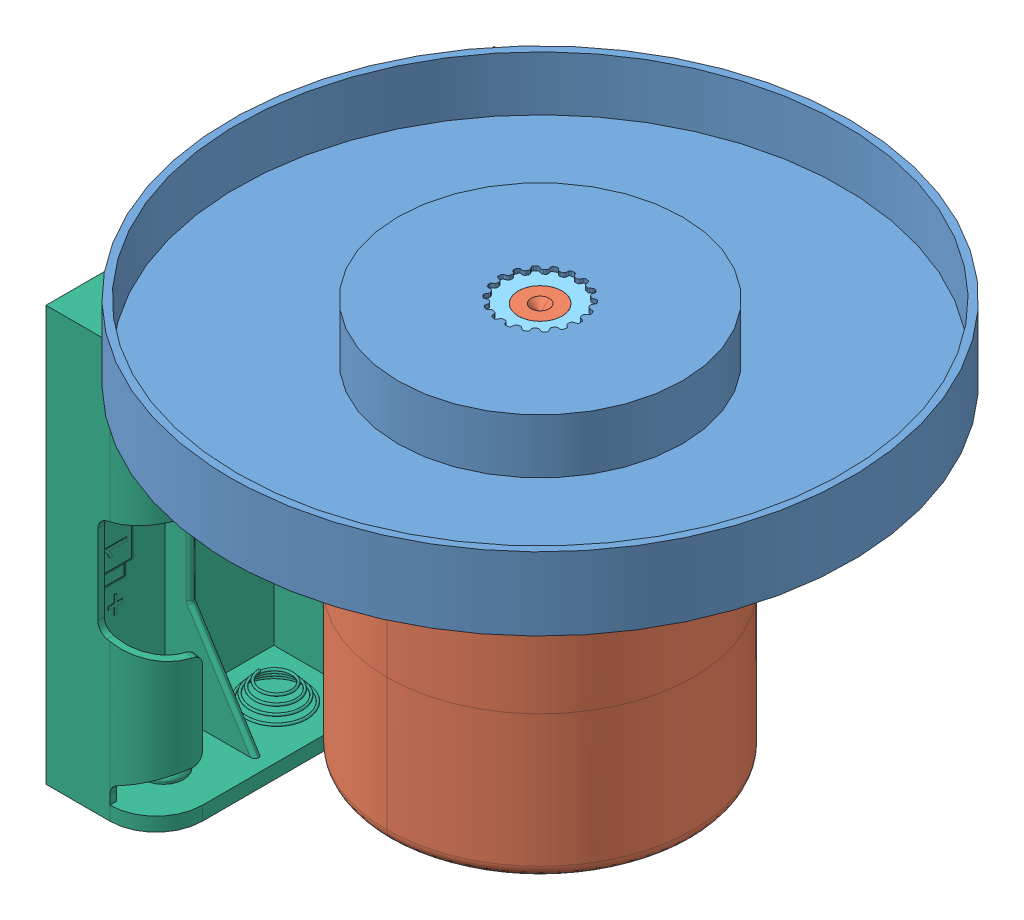
SolidWorks assembly Assem, configuration Default. Lengths in mm.
Overall size (93.99 75.26 87.69).
9 component instances, 6 part files, 2 mates.
Components (placement in the parent):
- Wheel-1: Wheel [Default] at (109.0913 123.8958 121.3791) size (85 10 85)
- Assem1.STEP-1: Assem1.STEP [Default] at (109.0913 99.4458 121.3791) size (69.62 53.75 56.99)
  - motor.STEP-1: motor.STEP [Default] at origin size (48.19 53.75 42)
  - mount_plate.STEP-1: mount_plate.STEP [Default] at (0 14.3 0) x (0.961464 0 -0.274932) z (0.274932 0 0.961464) size (60.4 5.33 42)
  - pan head cross recess screw_iso_ISO 7045 - M3 x 4 - Z - 4N.STEP-1: pan head cross recess screw_iso_ISO 7045 - M3 x 4 - Z - 4N.STEP [Default] at (0 17.78 -15) x (0 -1 0) z (0 0 1) size (6.36 5.6 5.6)
  - pan head cross recess screw_iso_ISO 7045 - M3 x 4 - Z - 4N.STEP-2: pan head cross recess screw_iso_ISO 7045 - M3 x 4 - Z - 4N.STEP [Default] at (-12.9904 17.78 7.5) x (0 -1 0) z (0 0 1) size (6.36 5.6 5.6)
  - pan head cross recess screw_iso_ISO 7045 - M3 x 4 - Z - 4N.STEP-3: pan head cross recess screw_iso_ISO 7045 - M3 x 4 - Z - 4N.STEP [Default] at (12.9904 17.78 7.5) x (0 -1 0) z (0 0 1) size (6.36 5.6 5.6)
  - pulley_nidec.STEP-1: pulley_nidec.STEP [Default] at (0 33.9 0) x (1 0 0) z (0 1 0) size (15 15 11.6)
- Battery2-1: Battery2 [Default] at (57.6046 87.0879 106.9276) x (0 1 0) z (1 0 0) size (59.56 61.47 15.11)
Mates (geometry in assembly coordinates):
- Concentric1: concentric aligned: circle of Wheel-1; circle of Assem1.STEP-1/pulley_nidec.STEP-1
- Coincident1: coincident anti-aligned: plane of Wheel-1 through (109.0913 123.8958 121.3791) normal (0 -1 0); plane of Assem1.STEP-1/pulley_nidec.STEP-1 through (109.0913 123.8958 121.3791) normal (0 1 0)
